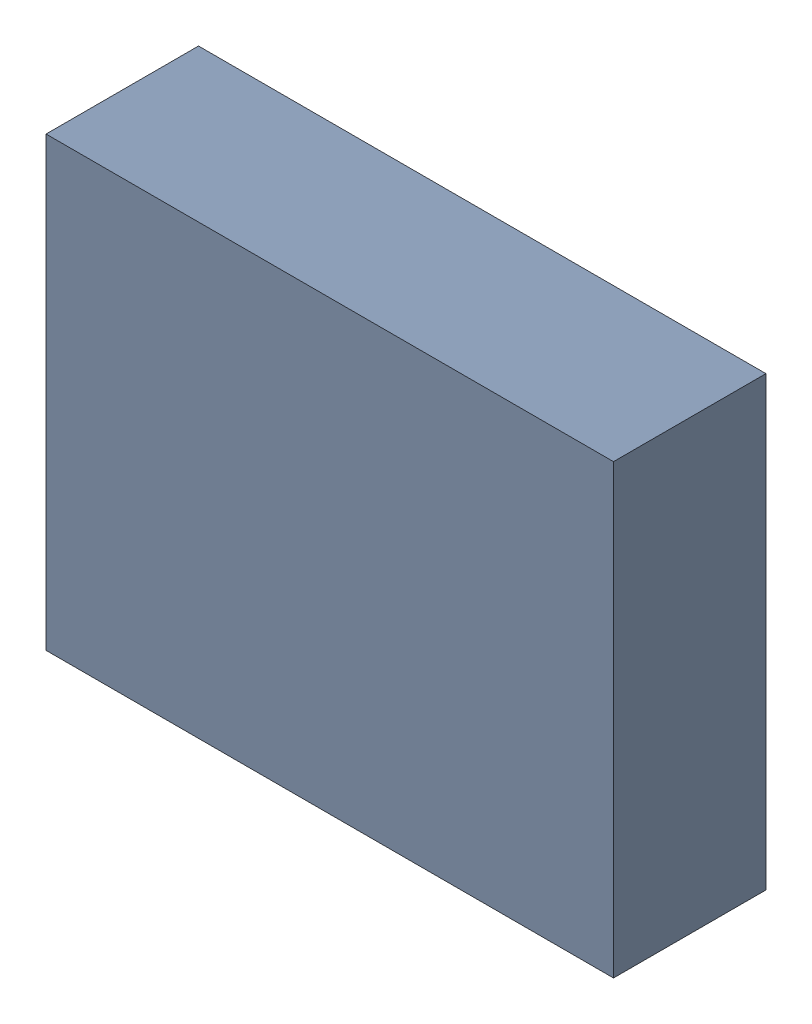
SolidWorks assembly R1, configuration Default. Lengths in mm.
Overall size (3.35 2.64 0.9).
2 component instances, 1 part files, 0 mates.
Components (placement in the parent):
- 5920132160-1: 5920132160 [Default] at (12 10 0) size (3.35 2.64 0.9)
  - Extruded-1: Extruded [Default] at origin size (3.35 2.64 0.9)
